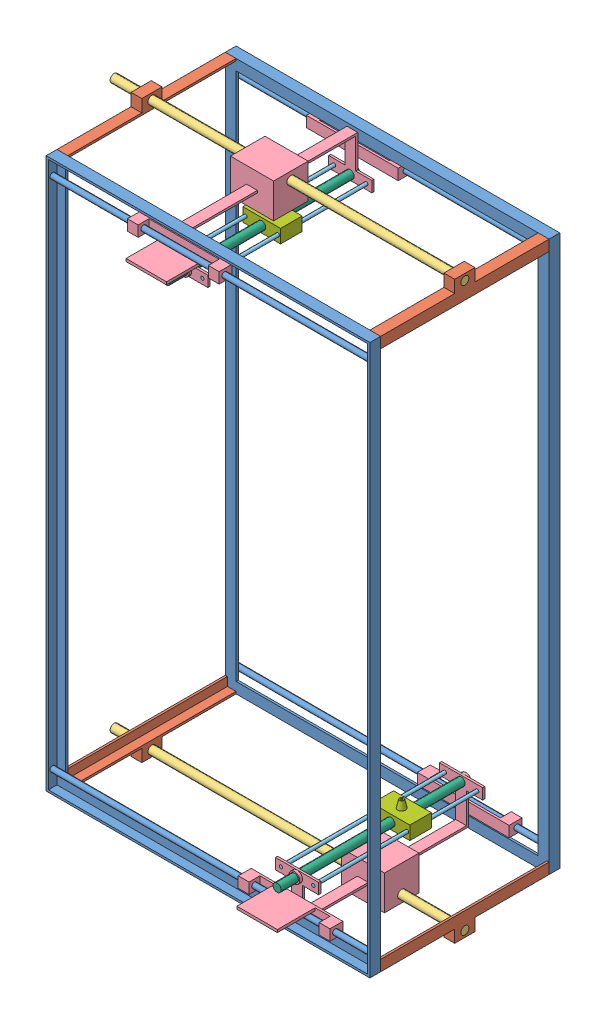
SolidWorks assembly Assem1, configuration Default. Lengths in mm.
Overall size (650 1072 406).
18 component instances, 7 part files, 39 mates.
Components (placement in the parent):
- grind1-1: grind1 [Default] at (-191.5962 76.5607 49.0885) size (600 1020 20)
- grind1-2: grind1 [Default] at (-191.5962 -53.1877 -262.9115) x (1 0 0) z (0 0 -1) size (600 1020 20)
- grind_vertical-1: grind_vertical [Default] at (-324.5505 512.2676 -262.9115) x (0 -1 0) z (0 0 1) size (43 20 312)
- grind_vertical-2: grind_vertical [Default] at (-324.5505 -488.8947 49.0885) x (0 1 0) z (0 0 -1) size (43 20 312)
- grind_vertical-3: grind_vertical [Default] at (256.9124 512.2676 49.0885) x (0 -1 0) z (0 0 -1) size (43 20 312)
- grind_vertical-4: grind_vertical [Default] at (256.9124 -488.8947 -262.9115) x (0 1 0) z (0 0 1) size (43 20 312)
- 15mm_horizontal-1: 15mm_horizontal [Default] at (266.181 533.1865 -106.9115) x (0 0 1) z (-1 0 0) size (15 15 650)
- 15mm_horizontal-2: 15mm_horizontal [Default] at (266.181 -509.8135 -106.9115) x (0 0.889081 0.457751) z (-1 0 0) size (15 15 650)
- sledi-1: sledi [Default] at (-86.3012 516.1434 -223.657) x (0 -1 0) z (-1 0 0) size (110 406 170)
- sledi-2: sledi [Default] at (99.1628 -492.7704 -223.657) x (0 1 0) z (1 0 0) size (110 406 170)
- 6mm-2: 6mm [Default] at (-126.3012 447.6865 -260.9115) size (6 6 308)
- 6mm-3: 6mm [Default] at (79.1628 -424.3135 -260.9115) size (6 6 308)
- 6mm-4: 6mm [Default] at (139.1628 -424.3135 -260.9115) size (6 6 308)
- 6mm-5: 6mm [Default] at (-66.3012 447.6865 -260.9115) size (6 6 308)
- 15mm_vertical-1: 15mm_vertical [Default] at (109.1628 -424.3135 -265.9115) x (0.999832 0.018357 0) z (0 0 1) size (15 15 350)
- 15mm_vertical-2: 15mm_vertical [Default] at (-96.3012 447.6865 -265.9115) size (15 15 350)
- vertical-1: vertical [Default] at (-83.4455 440.3468 -132.7776) size (70 39.04 40)
- vertical-2: vertical [Default] at (96.3071 -416.9738 -166.8792) x (-1 0 0) z (0 0 1) size (70 39.04 40)
Mates (geometry in assembly coordinates):
- Coincident1: coincident anti-aligned: plane of grind1-2 through (266.181 -498.3135 -262.9115) normal (0 0 1); plane of grind_vertical-4 through (266.181 -478.3135 -262.9115) normal (0 0 -1)
- Coincident2: coincident aligned: plane of grind1-2 through (266.181 521.6865 -262.9115) normal (1 0 0); plane of grind_vertical-4 through (266.181 -521.3135 -262.9115) normal (1 0 0)
- Coincident3: coincident aligned: plane of grind1-2 through (266.181 -498.3135 -262.9115) normal (0 -1 0); plane of grind_vertical-4 through (246.181 -498.3135 -262.9115) normal (0 -1 0)
- Coincident4: coincident aligned: plane of grind1-1 through (266.181 -498.3135 49.0885) normal (1 0 0); plane of grind_vertical-4 through (266.181 -521.3135 -262.9115) normal (1 0 0)
- Coincident5: coincident aligned: plane of grind1-1 through (-333.819 -498.3135 49.0885) normal (0 -1 0); plane of grind_vertical-4 through (246.181 -498.3135 -88.1615) normal (0 -1 0)
- Coincident6: coincident aligned: plane of grind1-1 through (-333.819 -498.3135 49.0885) normal (0 -1 0); plane of grind_vertical-2 through (-313.819 -498.3135 49.0885) normal (0 -1 0)
- Coincident7: coincident anti-aligned: plane of grind1-1 through (266.181 521.6865 49.0885) normal (0 0 -1); plane of grind_vertical-2 through (-333.819 -478.3135 49.0885) normal (0 0 1)
- Coincident8: coincident aligned: plane of grind1-1 through (-333.819 521.6865 49.0885) normal (-1 0 0); plane of grind_vertical-2 through (-333.819 -521.3135 49.0885) normal (-1 0 0)
- Coincident9: coincident aligned: plane of grind1-1 through (-333.819 521.6865 49.0885) normal (-1 0 0); plane of grind_vertical-1 through (-333.819 544.6865 -262.9115) normal (-1 0 0)
- Coincident10: coincident anti-aligned: plane of grind1-2 through (266.181 -498.3135 -262.9115) normal (0 0 1); plane of grind_vertical-1 through (-333.819 501.6865 -262.9115) normal (0 0 -1)
- Coincident11: coincident: line of grind1-2 through (-333.819 521.6865 -282.9115) axis (1 0 0); plane of grind_vertical-1 through (-313.819 521.6865 -262.9115) normal (0 1 0)
- Coincident12: coincident aligned: plane of grind1-1 through (266.181 -498.3135 49.0885) normal (1 0 0); plane of grind_vertical-3 through (266.181 544.6865 49.0885) normal (1 0 0)
- Coincident13: coincident aligned: plane of grind1-1 through (266.181 521.6865 49.0885) normal (0 1 0); plane of grind_vertical-3 through (246.181 521.6865 49.0885) normal (0 1 0)
- Coincident14: coincident anti-aligned: plane of grind1-1 through (266.181 521.6865 49.0885) normal (0 0 -1); plane of grind_vertical-3 through (266.181 501.6865 49.0885) normal (0 0 1)
- Concentric1: concentric aligned: cylinder of grind_vertical-3 through (246.181 533.1865 -106.9115) axis (-1 0 0) radius 7.5; cylinder of 15mm_horizontal-1 through (266.181 533.1865 -106.9115) axis (-1 0 0) radius 7.5
- Coincident15: coincident aligned: plane of grind_vertical-3 through (266.181 544.6865 49.0885) normal (1 0 0); plane of 15mm_horizontal-1 through (266.181 533.1865 -99.4115) normal (1 0 0)
- Concentric2: concentric anti-aligned: cylinder of 15mm_horizontal-1 through (266.181 533.1865 -106.9115) axis (-1 0 0) radius 7.5; cylinder of sledi-1 through (-136.3012 533.1865 -106.9115) axis (1 0 0) radius 7.5
- Concentric3: concentric aligned: cylinder of grind1-1 through (-329.819 487.6865 61.0885) axis (1 0 0) radius 5; cylinder of sledi-1 through (-31.3012 487.6865 61.0885) axis (1 0 0) radius 5
- Concentric4: concentric anti-aligned: cylinder of sledi-1 through (-96.3012 447.6865 52.0885) axis (0 0 -1) radius 7.5; cylinder of 15mm_vertical-2 through (-96.3012 447.6865 -265.9115) axis (0 0 1) radius 7.5
- Concentric5: concentric anti-aligned: cylinder of sledi-1 through (-66.3012 447.6865 47.0885) axis (0 0 -1) radius 3; cylinder of 6mm-5 through (-66.3012 447.6865 -260.9115) axis (0 0 1) radius 3
- Coincident16: coincident aligned: plane of sledi-1 through (-86.3012 517.6865 47.0885) normal (0 0 1); plane of 6mm-5 through (-66.3012 447.6865 47.0885) normal (0 0 1)
- Coincident17: coincident aligned: plane of sledi-1 through (-96.3012 447.6865 -265.9115) normal (0 0 -1); plane of 15mm_vertical-2 through (-88.8012 447.6865 -265.9115) normal (0 0 -1)
- Concentric6: concentric aligned: cylinder of sledi-1 through (-126.3012 447.6865 -260.9115) axis (0 0 1) radius 3; cylinder of 6mm-2 through (-126.3012 447.6865 -260.9115) axis (0 0 1) radius 3
- Coincident18: coincident aligned: plane of sledi-1 through (-86.3012 437.6865 -260.9115) normal (0 0 -1); plane of 6mm-2 through (-123.3012 447.6865 -260.9115) normal (0 0 -1)
- Concentric7: concentric aligned: cylinder of 15mm_vertical-2 through (-96.3012 447.6865 -265.9115) axis (0 0 1) radius 7.5; cylinder of vertical-1 through (-96.3012 447.6865 -92.7776) axis (0 0 1) radius 7.5
- Parallel1: parallel aligned: plane of sledi-1 through (-106.3012 483.6865 -138.9115) normal (0 -1 0); plane of vertical-1 through (-131.3012 435.1865 -132.7776) normal (0 -1 0)
- Concentric8: concentric anti-aligned: cylinder of grind1-2 through (-329.819 -464.3135 -274.9115) axis (1 0 0) radius 5; cylinder of sledi-2 through (44.1628 -464.3135 -274.9115) axis (-1 0 0) radius 5
- Concentric9: concentric anti-aligned: cylinder of grind_vertical-2 through (-313.819 -509.8135 -106.9115) axis (1 0 0) radius 7.5; cylinder of 15mm_horizontal-2 through (266.181 -509.8135 -106.9115) axis (-1 0 0) radius 7.5
- Coincident19: coincident aligned: plane of grind_vertical-4 through (266.181 -521.3135 -262.9115) normal (1 0 0); plane of 15mm_horizontal-2 through (266.181 -503.1454 -103.4784) normal (1 0 0)
- Coincident20: coincident anti-aligned: plane of grind1-2 through (266.181 -498.3135 -262.9115) normal (0 0 1); plane of grind_vertical-2 through (-333.819 -521.3135 -262.9115) normal (0 0 -1)
- Concentric10: concentric aligned: cylinder of 15mm_horizontal-2 through (266.181 -509.8135 -106.9115) axis (-1 0 0) radius 7.5; cylinder of sledi-2 through (149.1628 -509.8135 -106.9115) axis (-1 0 0) radius 7.5
- Concentric11: concentric anti-aligned: cylinder of sledi-2 through (109.1628 -424.3135 52.0885) axis (0 0 -1) radius 7.5; cylinder of 15mm_vertical-1 through (109.1628 -424.3135 -271.9438) axis (0 0 1) radius 7.5
- Concentric12: concentric anti-aligned: cylinder of sledi-2 through (79.1628 -424.3135 47.0885) axis (0 0 -1) radius 3; cylinder of 6mm-3 through (79.1628 -424.3135 -260.9115) axis (0 0 1) radius 3
- Coincident22: coincident aligned: plane of sledi-2 through (99.1628 -494.3135 47.0885) normal (0 0 1); plane of 6mm-3 through (79.1628 -424.3135 47.0885) normal (0 0 1)
- Concentric13: concentric anti-aligned: cylinder of sledi-2 through (139.1628 -424.3135 47.0885) axis (0 0 -1) radius 3; cylinder of 6mm-4 through (139.1628 -424.3135 -260.9115) axis (0 0 1) radius 3
- Coincident23: coincident aligned: plane of sledi-2 through (99.1628 -494.3135 47.0885) normal (0 0 1); plane of 6mm-4 through (139.1628 -424.3135 47.0885) normal (0 0 1)
- Concentric14: concentric aligned: cylinder of 15mm_vertical-1 through (109.1628 -424.3135 -271.9438) axis (0 0 1) radius 7.5; cylinder of vertical-2 through (109.1628 -424.3135 -126.8792) axis (0 0 1) radius 7.5
- Parallel2: parallel aligned: plane of sledi-2 through (119.1628 -460.3135 -138.9115) normal (0 1 0); plane of vertical-2 through (144.1628 -411.8135 -166.8792) normal (0 1 0)
- Coincident24: coincident aligned: plane of sledi-2 through (109.1628 -424.3135 -265.9115) normal (0 0 -1); plane of 15mm_vertical-1 through (116.6616 -424.1758 -265.9115) normal (0 0 -1)
